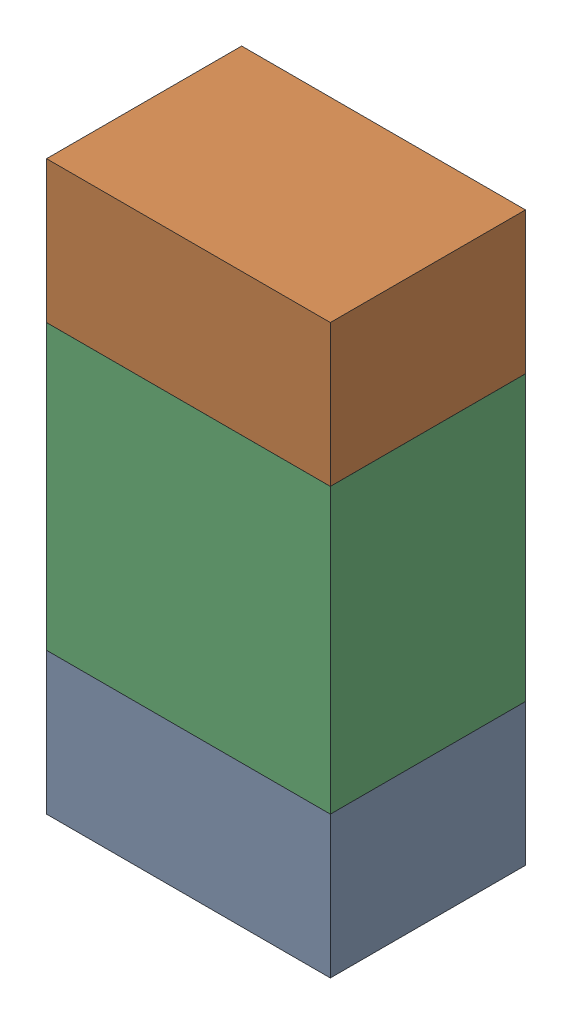
SolidWorks assembly R59, configuration ﾃﾞﾌｫﾙﾄ. Lengths in mm.
Overall size (0.8 1.6 0.55).
6 component instances, 2 part files, 0 mates.
Components (placement in the parent):
- 689261784-1: 689261784 [ﾃﾞﾌｫﾙﾄ] at (28.8926 15.2751 -1.7503) size (0.8 0.4 0.55)
  - Extruded_34-1: Extruded_34 [ﾃﾞﾌｫﾙﾄ] at origin size (0.8 0.4 0.55)
- 689261784-2: 689261784 [ﾃﾞﾌｫﾙﾄ] at (28.8926 16.4751 -1.7503) size (0.8 0.4 0.55)
  - Extruded_34-1: Extruded_34 [ﾃﾞﾌｫﾙﾄ] at origin size (0.8 0.4 0.55)
- 689261648-1: 689261648 [ﾃﾞﾌｫﾙﾄ] at (28.8926 15.875 -1.7503) size (0.8 0.8 0.55)
  - Extruded_33-1: Extruded_33 [ﾃﾞﾌｫﾙﾄ] at origin size (0.8 0.8 0.55)
